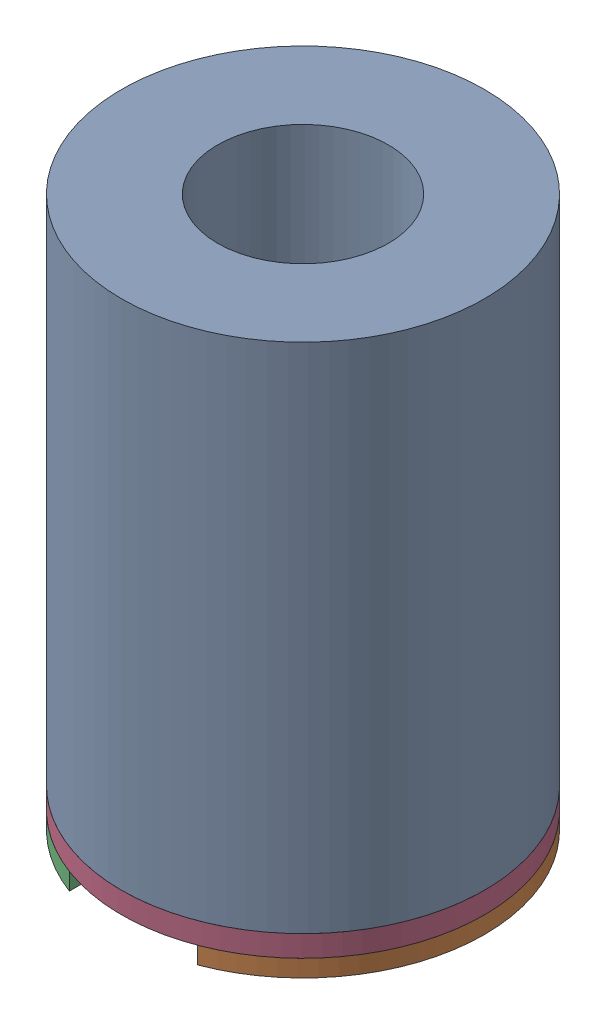
SolidWorks assembly AirCore_Assembly, configuration Default. Lengths in mm.
Overall size (5.76 6.45 5.76).
3 component instances, 3 part files, 3 mates.
Components (placement in the parent):
- AirCore_Coil-1: AirCore_Coil [Default] at (-0.6126 -1.7805 1.5329) size (4.25 6 4.25)
- AirCore_SolderPads-1: AirCore_SolderPads [Default] at (-0.6126 -2.0305 1.5329) x (-0.001357 0 -0.999999) z (-0.999999 0 0.001357) size (3.98 0.2 4.25)
- AirCore_Base-1: AirCore_Base [Default] at (-0.6126 -1.7805 1.5329) x (-0.47657 0 -0.879137) z (-0.879137 0 0.47657) size (4.25 0.25 4.25)
Mates (geometry in assembly coordinates):
- Coincident1: coincident anti-aligned: plane of AirCore_Coil-1 through (-0.6126 -1.7805 1.5329) normal (0 -1 0); plane of AirCore_Base-1 through (-0.6126 -1.7805 1.5329) normal (0 1 0)
- Concentric1: concentric anti-aligned: circle of AirCore_Coil-1; circle of AirCore_Base-1
- Coincident3: coincident aligned: circle of AirCore_SolderPads-1; circle of AirCore_Base-1
